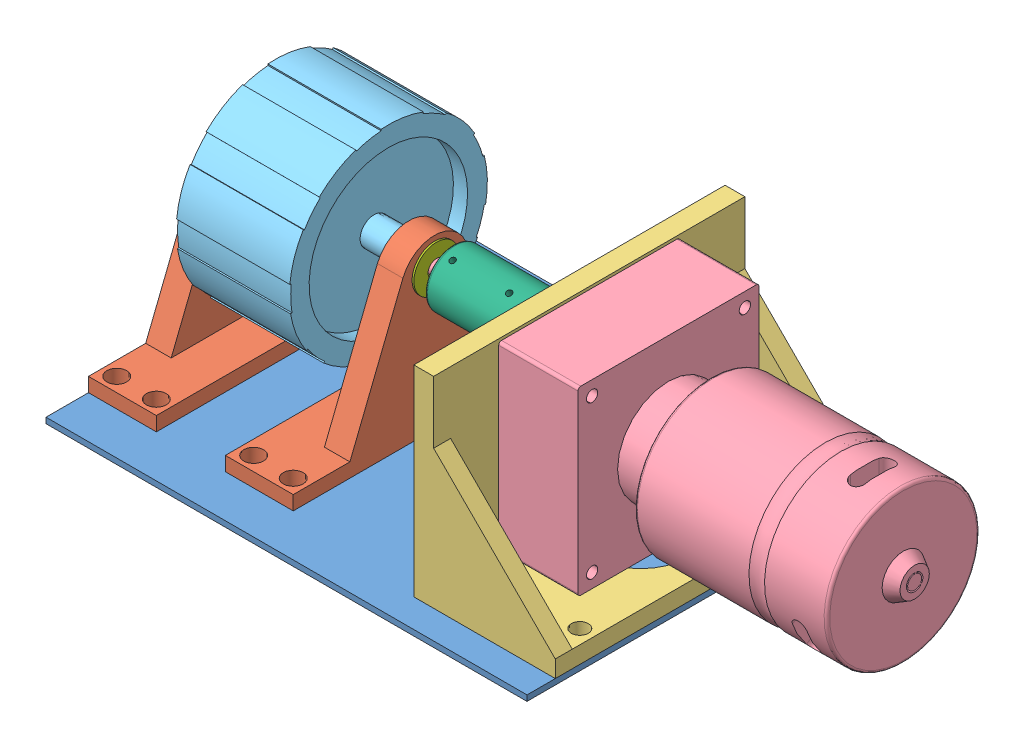
SolidWorks assembly pole clib part 1, configuration Default. Lengths in mm.
Overall size (242.35 94.18 130).
9 component instances, 7 part files, 17 mates.
Components (placement in the parent):
- base-1: base [Default] at (31.7698 -36.7623 7.5319) size (170 2 130)
- part2v2-1: part2v2 [Default] at (-41.2302 -34.7623 7.5319) x (0 0 1) z (-1 0 0) size (100 59.4 24)
- part2v2-2: part2v2 [Default] at (7.1483 -34.7623 7.5319) x (0 0 -1) z (1 0 0) size (100 59.4 24)
- motor holder-1: motor holder [Default] at (91.7698 -34.7623 7.5316) x (0 0 1) z (-1 0 0) size (110 71 50)
- motor-1: motor [Default] at (73.7698 3.2377 7.5316) x (0 0 1) z (0 1 0) size (64 240 64)
- wheel-1: wheel [Default] at (-37.2381 15.2377 7.5316) x (0 -0.971221 -0.238181) z (0 -0.238181 0.971221) size (69.84 50 70)
- coupler-1: coupler [Default] at (65.5971 15.2377 7.5316) x (0 0.42254 -0.906344) z (0 0.906344 0.42254) size (20 40 20)
- bearing-1: bearing [Default] at (-53.577 14.8159 7.5319) x (0 -0.990765 0.135587) z (0 0.135587 0.990765) size (16 10 16)
- bearing-2: bearing [Default] at (19.7953 14.8159 7.5319) x (0 0.970411 -0.241458) z (0 0.241458 0.970411) size (16 10 16)
Mates (geometry in assembly coordinates):
- Concentric3: concentric aligned: circle of base-1; circle of part2v2-1
- Concentric4: concentric aligned: circle of base-1; circle of part2v2-1
- Concentric5: concentric aligned: circle of base-1; circle of part2v2-2
- Concentric6: concentric aligned: circle of base-1; circle of part2v2-2
- Coincident4: coincident anti-aligned: plane of base-1 through (31.7698 -34.7623 7.5319) normal (0 1 0); plane of part2v2-2 through (7.1483 -34.7623 7.5319) normal (0 -1 0)
- Coincident5: coincident anti-aligned: plane of base-1 through (31.7698 -34.7623 7.5319) normal (0 1 0); plane of part2v2-1 through (-41.2302 -34.7623 7.5319) normal (0 -1 0)
- Concentric7: concentric aligned: circle of base-1; circle of motor holder-1
- Concentric8: concentric aligned: circle of base-1; circle of motor holder-1
- Coincident8: coincident anti-aligned: plane of base-1 through (31.7698 -34.7623 7.5319) normal (0 1 0); plane of motor holder-1 through (91.7698 -34.7623 7.5316) normal (0 -1 0)
- Lock1: lock: unknown of motor holder-1; unknown of motor-1
- Concentric9: concentric anti-aligned: circle of motor holder-1; circle of motor-1
- Lock2: lock: unknown of motor-1; unknown of wheel-1
- Concentric11: concentric anti-aligned: cylinder of motor-1 through (-51.2302 15.2377 7.5316) axis (1 0 0) radius 2.5; cylinder of coupler-1 through (65.5971 15.2377 7.5316) axis (-1 0 0) radius 3
- Parallel1: parallel anti-aligned: plane of coupler-1 through (25.5971 15.2377 7.5316) normal (-1 0 0); plane of bearing-1 through (-43.577 14.8159 7.5319) normal (1 0 0)
- Concentric14: concentric anti-aligned: cylinder of part2v2-1 through (-53.2303 14.8159 7.5319) axis (1 0 0) radius 8; cylinder of bearing-1 through (-43.577 14.8159 7.5319) axis (-1 0 0) radius 8
- Parallel3: parallel anti-aligned: plane of wheel-1 through (-2.2381 15.2377 7.5316) normal (1 0 0); plane of bearing-2 through (9.7953 14.8159 7.5319) normal (-1 0 0)
- Concentric16: concentric anti-aligned: cylinder of part2v2-2 through (19.1484 14.8159 7.5319) axis (-1 0 0) radius 8; cylinder of bearing-2 through (9.7953 14.8159 7.5319) axis (1 0 0) radius 8
